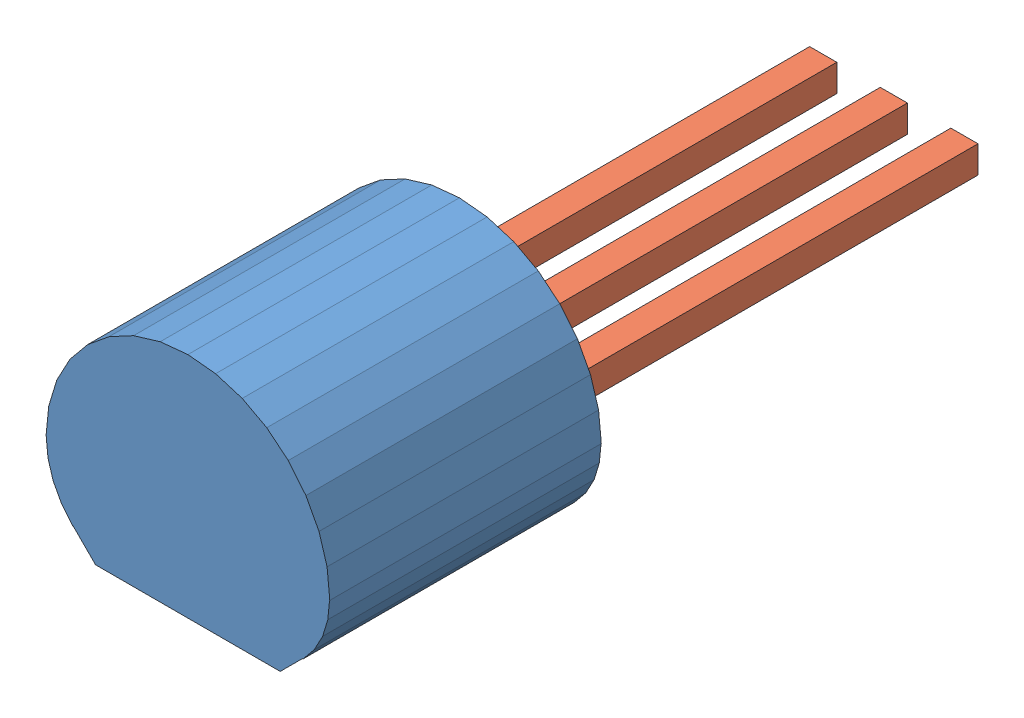
SolidWorks assembly User Library-TO-92_Str, configuration Default. Lengths in mm.
Overall size (5.23 4.2 13).
11 component instances, 2 part files, 0 mates.
Components (placement in the parent):
- User Library-TO-92_Str_Free-Models-1: User Library-TO-92_Str_Free-Models [Default] at origin size (5.23 4.2 13)
  - User Library-TO-92_Str_BODY-1: User Library-TO-92_Str_BODY [Default] at origin size (5.23 4.2 5)
    - User Library-TO-92_Str_Open_CASCADE_STEP_translator_6.2_1.1-1: User Library-TO-92_Str_Open_CASCADE_STEP_translator_6.2_1.1 [Default] at origin size (5.23 4.2 5)
      - User Library-TO-92_Str_547225856-1: User Library-TO-92_Str_547225856 [Default] at (0 0.5113 5) size (5.23 4.2 5)
        - User Library-TO-92_Str_Extruded-1: User Library-TO-92_Str_Extruded [Default] at origin size (5.23 4.2 5)
  - User Library-TO-92_Str_577959568-1: User Library-TO-92_Str_577959568 [Default] at (1.3 0 -3) size (0.5 0.5 8)
    - User Library-TO-92_Str_Extruded_2-1: User Library-TO-92_Str_Extruded_2 [Default] at origin size (0.5 0.5 8)
  - User Library-TO-92_Str_577959568-2: User Library-TO-92_Str_577959568 [Default] at (0 0 -3) size (0.5 0.5 8)
    - User Library-TO-92_Str_Extruded_2-1: User Library-TO-92_Str_Extruded_2 [Default] at origin size (0.5 0.5 8)
  - User Library-TO-92_Str_577959568-3: User Library-TO-92_Str_577959568 [Default] at (-1.3 0 -3) size (0.5 0.5 8)
    - User Library-TO-92_Str_Extruded_2-1: User Library-TO-92_Str_Extruded_2 [Default] at origin size (0.5 0.5 8)
